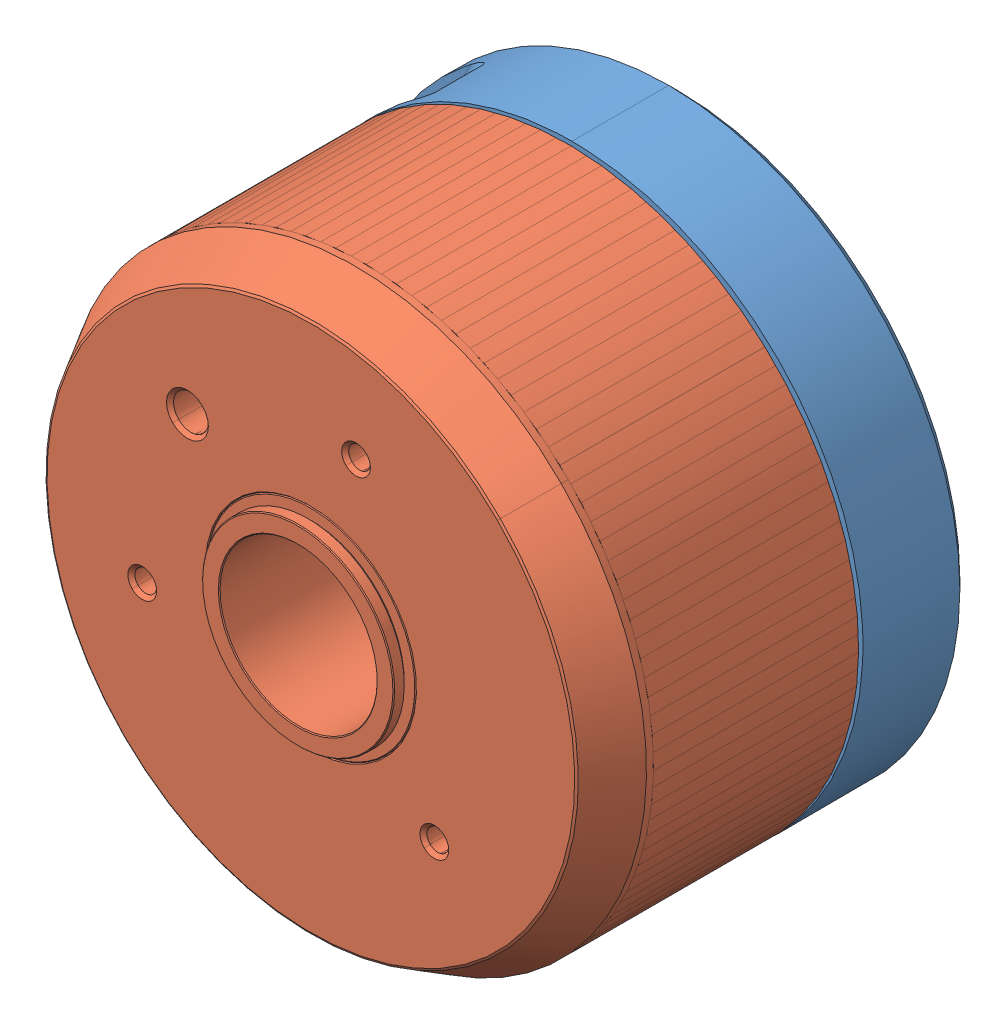
SolidWorks assembly GM6020, configuration Default. Lengths in mm.
Overall size (94.25 94.25 45).
2 component instances, 2 part files, 2 mates.
Components (placement in the parent):
- RoboMaster GM6020 直流无刷电机定子-1: RoboMaster GM6020 直流无刷电机定子 [默认] at (-102.0984 6.0825 161.2414) size (66.7 66.7 14.1)
- RoboMaster GM6020 直流无刷电机-1: RoboMaster GM6020 直流无刷电机 [默认] at (-102.0984 6.0825 161.2414) x (-0.677708 -0.735331 0) z (0 0 1) size (66.7 66.7 30.9)
Mates (geometry in assembly coordinates):
- 重合1: coincident: plane of RoboMaster GM6020 直流无刷电机定子-1 through (-102.0984 -27.27 56.7936) normal (0 0 1); plane of RoboMaster GM6020 直流无刷电机-1 through (-102.0984 6.0825 56.7936) normal (0 0 -1)
- 同心1: concentric: cylinder of RoboMaster GM6020 直流无刷电机定子-1 through (-102.0984 6.0825 88.2436) axis (0 0 -1) radius 9; cylinder of RoboMaster GM6020 直流无刷电机-1 through (-102.0984 6.0825 88.2436) axis (0 0 -1) radius 9
